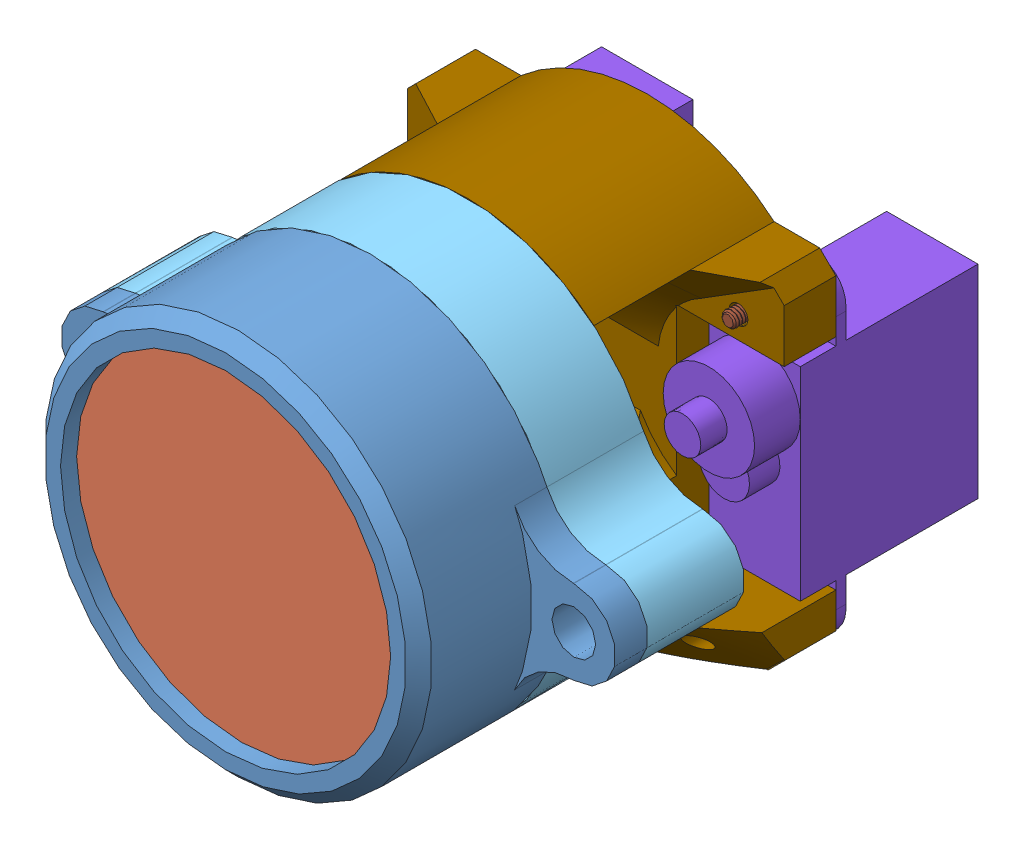
SolidWorks assembly Hydraulic Pressure Indicator, configuration Default. Lengths in mm.
Overall size (127.75 115.27 55.56).
32 component instances, 13 part files, 73 mates.
Components (placement in the parent):
- 1.5 IN Case-1: 1.5 IN Case [Default] x (1 0 0) z (0 -1 0) size (54.61 14.29 38.1)
- 1.5 Indicator Glass-1: 1.5 Indicator Glass [Default] at (0 0 -1.5875) x (-1 0 0) z (0 0 -1) size (32.84 32.84 1.59)
- Battery Voltage Indicator Spacer-1: Battery Voltage Indicator Spacer [Default] at (0 0 -3.175) x (-1 0 0) z (0 0 -1) size (32.84 32.84 6.35)
- Hydraulic Indicator Bezel Face-1: Hydraulic Indicator Bezel Face [Default] at (0 0 -11.1125) x (-1 0 0) z (0 0 1) size (32.84 32.84 1.59)
- 1.5 Indicator Rear Bezel Spacer-1: 1.5 Indicator Rear Bezel Spacer [Default] at (0 0 -11.1125) x (1 0 0) z (0 0 -1) size (54.61 38.1 12.7)
- Hydraulic Pressure Pointer-1: Hydraulic Pressure Pointer [#1 Needle] at (0 0 -8.7312) x (-0.207912 0.978148 0) z (0 0 1) size (8.26 18.1 1.59)
- Hydraulic Pressure Pointer-2: Hydraulic Pressure Pointer [#2 Needle] at (0 0 -6.35) x (-0.207912 0.978148 0) z (0 0 1) size (8.26 18.1 1.59)
- 93365A130_BRASS HEAT-SET INSERT FOR PLASTICS_6-32-3: 93365A130_BRASS HEAT-SET INSERT FOR PLASTICS_6-32 [93365A130] at (23.1775 0 -14.2875) x (1 0 0) z (0 -1 0) size (5.56 4.29 5.56)
- 93365A130_BRASS HEAT-SET INSERT FOR PLASTICS_6-32-4: 93365A130_BRASS HEAT-SET INSERT FOR PLASTICS_6-32 [93365A130] at (-23.1775 0 -14.2875) x (1 0 0) z (0 -1 0) size (5.56 4.29 5.56)
- spur gear_ai-1: spur gear_ai [PreviewCfg] at (0 0 -24.6062) x (0 0 -1) z (0.923728 0.383049 0) size (12.7 86.43 86.43)
- spur gear_ai-2: spur gear_ai [PreviewCfg] at (-14.0335 2.325 -27.7812) x (0 0 1) z (-1 0 0) size (12.7 86.43 86.43)
- spur gear_ai-3: spur gear_ai [PreviewCfg] at (0 0 -29.3687) x (0 0 -1) z (0.923728 0.383049 0) size (12.7 86.43 86.43)
- spur gear_ai-4: spur gear_ai [PreviewCfg] at (14.0335 2.325 -32.5438) x (0 0 1) z (-0.923728 -0.383049 0) size (12.7 86.43 86.43)
- SERVO, SUB-NANO, 3.7G, GENERIC-3: SERVO, SUB-NANO, 3.7G, GENERIC [Default] at (9.5335 -13.175 -55.5562) size (9.5 32.5 24.6)
- SERVO, SUB-NANO, 3.7G, GENERIC-4: SERVO, SUB-NANO, 3.7G, GENERIC [Default] at (-18.5335 -13.175 -55.5562) size (9.5 32.5 24.6)
- HYD PRESS SERVO MOUNT-1: HYD PRESS SERVO MOUNT [Default] at (0 0 -23.8125) x (1 0 0) z (0 0 -1) size (37.07 38.1 17.74)
- 93365A102 - INSERT, 0-80, BRASS, FOR PLASTICS-1: 93365A102 - INSERT, 0-80, BRASS, FOR PLASTICS [Default] at (-14.0335 -16.175 -41.5563) x (-0.425487 0.904965 0) z (-0.904965 -0.425487 0) size (3.58 3.01 3.58)
- 91772A061_18-8 SS PAN HEAD PHILLIPS MACHINE SCREW_#0-80 X .2812-1: 91772A061_18-8 SS PAN HEAD PHILLIPS MACHINE SCREW_#0-80 X .2812 [91772A061] at (-14.0335 -16.175 -35.4125) x (-0.994174 -0.107783 0) z (0 0 -1) size (2.95 2.95 8.26)
- 91772A061_18-8 SS PAN HEAD PHILLIPS MACHINE SCREW_#0-80 X .2812-2: 91772A061_18-8 SS PAN HEAD PHILLIPS MACHINE SCREW_#0-80 X .2812 [91772A061] at (14.0335 9.825 -35.4125) x (-0.994174 -0.107783 0) z (0 0 -1) size (2.95 2.95 8.26)
- 91772A061_18-8 SS PAN HEAD PHILLIPS MACHINE SCREW_#0-80 X .2812-3: 91772A061_18-8 SS PAN HEAD PHILLIPS MACHINE SCREW_#0-80 X .2812 [91772A061] at (-14.0335 9.825 -35.4125) x (-0.994174 -0.107783 0) z (0 0 -1) size (2.95 2.95 8.26)
- 91772A061_18-8 SS PAN HEAD PHILLIPS MACHINE SCREW_#0-80 X .2812-4: 91772A061_18-8 SS PAN HEAD PHILLIPS MACHINE SCREW_#0-80 X .2812 [91772A061] at (14.0335 -16.175 -35.4125) x (-0.994174 -0.107783 0) z (0 0 -1) size (2.95 2.95 8.26)
- 93365A102 - INSERT, 0-80, BRASS, FOR PLASTICS-2: 93365A102 - INSERT, 0-80, BRASS, FOR PLASTICS [Default] at (14.0335 9.825 -41.5563) x (-0.425487 0.904965 0) z (-0.904965 -0.425487 0) size (3.58 3.01 3.58)
- 93365A102 - INSERT, 0-80, BRASS, FOR PLASTICS-3: 93365A102 - INSERT, 0-80, BRASS, FOR PLASTICS [Default] at (-14.0335 9.825 -41.5563) x (-0.425487 0.904965 0) z (-0.904965 -0.425487 0) size (3.58 3.01 3.58)
- 93365A102 - INSERT, 0-80, BRASS, FOR PLASTICS-4: 93365A102 - INSERT, 0-80, BRASS, FOR PLASTICS [Default] at (14.0335 -16.175 -41.5563) x (-0.425487 0.904965 0) z (-0.904965 -0.425487 0) size (3.58 3.01 3.58)
- 91772A064 - PHS, 0-80 x .4375, 18-8-1: 91772A064 - PHS, 0-80 x .4375, 18-8 [91772A064] at (7.435 -14.6946 -28.575) x (-0.345103 0.938565 0) z (0 0 1) size (2.95 2.95 12.24)
- 93365A102 - INSERT, 0-80, BRASS, FOR PLASTICS-5: 93365A102 - INSERT, 0-80, BRASS, FOR PLASTICS [Default] at (7.435 -14.6946 -23.8125) x (-0.142747 -0.989759 0) z (-0.989759 0.142747 0) size (3.58 3.01 3.58)
- 93365A102 - INSERT, 0-80, BRASS, FOR PLASTICS-6: 93365A102 - INSERT, 0-80, BRASS, FOR PLASTICS [Default] at (-7.7474 -14.6946 -23.8125) x (-0.142747 -0.989759 0) z (-0.989759 0.142747 0) size (3.58 3.01 3.58)
- 93365A102 - INSERT, 0-80, BRASS, FOR PLASTICS-7: 93365A102 - INSERT, 0-80, BRASS, FOR PLASTICS [Default] at (-7.7474 14.6946 -23.8125) x (-0.142747 -0.989759 0) z (-0.989759 0.142747 0) size (3.58 3.01 3.58)
- 93365A102 - INSERT, 0-80, BRASS, FOR PLASTICS-8: 93365A102 - INSERT, 0-80, BRASS, FOR PLASTICS [Default] at (7.435 14.6946 -23.8125) x (-0.142747 -0.989759 0) z (-0.989759 0.142747 0) size (3.58 3.01 3.58)
- 91772A064 - PHS, 0-80 x .4375, 18-8-2: 91772A064 - PHS, 0-80 x .4375, 18-8 [91772A064] at (-7.7474 -14.6946 -28.575) x (-0.345103 0.938565 0) z (0 0 1) size (2.95 2.95 12.24)
- 91772A064 - PHS, 0-80 x .4375, 18-8-3: 91772A064 - PHS, 0-80 x .4375, 18-8 [91772A064] at (-7.7474 14.6946 -28.575) x (-0.345103 0.938565 0) z (0 0 1) size (2.95 2.95 12.24)
- 91772A064 - PHS, 0-80 x .4375, 18-8-4: 91772A064 - PHS, 0-80 x .4375, 18-8 [91772A064] at (7.435 14.6946 -28.575) x (-0.345103 0.938565 0) z (0 0 1) size (2.95 2.95 12.24)
Mates (geometry in assembly coordinates):
- Coincident1: coincident aligned: plane of 1.5 IN Case-1 through (0 0 0) normal (1 0 0); plane of assembly through (0 0 0) normal (1 0 0)
- Coincident2: coincident aligned: plane of 1.5 IN Case-1 through (0 0 0) normal (0 0 1); plane of assembly through (0 0 0) normal (0 0 1)
- Coincident3: coincident anti-aligned: plane of 1.5 IN Case-1 through (0 0 0) normal (0 -1 0); plane of assembly through (0 0 0) normal (0 1 0)
- InPlace1: in place: plane of 1.5 IN Case-1 through (0 0 -1.5875) normal (0 0 -1); plane of 1.5 Indicator Glass-1 through (0 0 -1.5875) normal (0 0 -1); moOrthogonalPlaneRef_w of 1.5 IN Case-1 through (0 0 -1.5875) normal (0 0 -1); unknown of 1.5 Indicator Glass-1; plane of 1.5 IN Case-1 through (0 0 -1.5875) normal (0 0 -1); plane of 1.5 Indicator Glass-1 through (0 0 -1.5875) normal (-1 0 0); plane of 1.5 IN Case-1 through (0 0 -1.5875) normal (0 0 -1); unknown of 1.5 Indicator Glass-1
- Coincident4: coincident aligned: plane of ?; plane of ?
- Coincident5: coincident aligned: moOrthogonalPlaneRef_w of 1.5 IN Case-1 through (0 0 -1.5875) normal (0 1 0); plane of 1.5 Indicator Glass-1 through (0 0 -1.5875) normal (0 1 0)
- Coincident6: coincident anti-aligned: moOrthogonalPlaneRef_w of 1.5 IN Case-1 through (0 0 -1.5875) normal (1 0 0); plane of 1.5 Indicator Glass-1 through (0 0 -1.5875) normal (-1 0 0)
- InPlace2: in place: plane of 1.5 Indicator Glass-1 through (0 0 -3.175) normal (0 0 -1); plane of Battery Voltage Indicator Spacer-1 through (0 0 -3.175) normal (0 0 -1); plane of 1.5 Indicator Glass-1 through (0 0 -3.175) normal (0 0 -1); unknown of Battery Voltage Indicator Spacer-1; plane of 1.5 Indicator Glass-1 through (0 0 -3.175) normal (0 0 -1); plane of Battery Voltage Indicator Spacer-1 through (0 0 -3.175) normal (-1 0 0); plane of 1.5 Indicator Glass-1 through (0 0 -3.175) normal (0 0 -1); unknown of Battery Voltage Indicator Spacer-1
- Coincident7: coincident aligned: plane of ?; plane of ?
- Coincident8: coincident aligned: moOrthogonalPlaneRef_w of 1.5 Indicator Glass-1 through (0 0 -3.175) normal (0 1 0); plane of Battery Voltage Indicator Spacer-1 through (0 0 -3.175) normal (0 1 0)
- Coincident9: coincident anti-aligned: moOrthogonalPlaneRef_w of 1.5 Indicator Glass-1 through (0 0 -3.175) normal (1 0 0); plane of Battery Voltage Indicator Spacer-1 through (0 0 -3.175) normal (-1 0 0)
- Concentric1: concentric anti-aligned: cylinder of 1.5 IN Case-1 through (0 0 -1.5875) axis (0 0 1) radius 19.05; cylinder of Hydraulic Indicator Bezel Face-1 through (0 0 -9.525) axis (0 0 -1) radius 16.4211
- Coincident13: coincident anti-aligned: plane of Hydraulic Indicator Bezel Face-1 through (0 0 -11.1125) normal (-1 0 0); plane of assembly through (0 0 0) normal (1 0 0)
- Coincident14: coincident anti-aligned: plane of Battery Voltage Indicator Spacer-1 through (0 0 -9.525) normal (0 0 -1); plane of Hydraulic Indicator Bezel Face-1 through (0 0 -9.525) normal (0 0 1)
- InPlace5: in place: plane of ? through (0 0 -32.6375) normal (0 0 -1); plane of ? through (0 0 -32.6375) normal (0 0 -1); plane of ? through (0 0 -32.6375) normal (0 0 -1); unknown of ?; plane of ? through (0 0 -32.6375) normal (0 0 -1); plane of ? through (0 0 -32.6375) normal (-1 0 0); plane of ? through (0 0 -40.9243) normal (0 0 -1); unknown of ?
- Coincident29: coincident aligned: plane of ?; plane of ?
- Coincident30: coincident aligned: moOrthogonalPlaneRef_w of Needle #2 Concentric Needle Shaft-1; plane of Needle #1 Concetric Needle Shaft-1 through (0 0 -28.4125) normal (0.190115 0.981762 0)
- Coincident31: coincident anti-aligned: moOrthogonalPlaneRef_w of Needle #2 Concentric Needle Shaft-1; plane of Needle #1 Concetric Needle Shaft-1 through (0 0 -28.4125) normal (-0.981762 0.190115 0)
- Concentric30: concentric aligned: cylinder of Needle #2 Concentric Needle Shaft-1 through (0 0 0.9475) axis (0 0 -1) radius 3.175; cylinder of Hydraulic Pressure Pointer-1 through (0 0 -7.1437) axis (0 0 -1) radius 3.302
- Concentric31: concentric: cylinder of Needle #1 Concetric Needle Shaft-1 through (0 0 -45.6026) axis (0 0 1) radius 1.5875; cylinder of Hydraulic Pressure Pointer-2 through (0 0 -4.7625) axis (0 0 -1) radius 1.651
- Coincident78: coincident: plane of ? through (0 0 -4.7625) normal (0 0 1); plane of Hydraulic Pressure Pointer-2 through (0 0 -4.7625) normal (0 0 1)
- Distance11: distance = 0.7937 mm: plane of Hydraulic Pressure Pointer-1 through (0 0 -7.1437) normal (0 0 1); plane of Hydraulic Pressure Pointer-2 through (0 0 -6.35) normal (0 0 -1)
- Width5: width anti-aligned: plane of Hydraulic Pressure Pointer-1 through (-3.3967 -2.345 -7.1437) normal (0.207912 -0.978148 0); plane of Hydraulic Indicator Bezel Face-1 through (-4.0568 0.7607 -7.1437) normal (-0.207912 0.978148 0); plane of Hydraulic Pressure Pointer-1 through (-13.3759 -3.1028 -9.525) normal (-0.207912 0.978148 0); plane of Hydraulic Indicator Bezel Face-1 through (-13.4815 -2.6059 -9.525) normal (0.207912 -0.978148 0)
- Coincident79: coincident aligned: plane of Hydraulic Pressure Pointer-1 through (-3.3967 -2.345 -7.1437) normal (0.207912 -0.978148 0); plane of Hydraulic Pressure Pointer-2 through (-3.3967 -2.345 -4.7625) normal (0.207912 -0.978148 0)
- Concentric63: concentric aligned: cylinder of Hydraulic Indicator Bezel Face-1 through (0 0 -9.525) axis (0 0 -1) radius 3.302; cylinder of VID28-05-1 through (0 0 -47.5625) axis (0 0 -1) radius 0.75
- Parallel5: parallel aligned: plane of VID28-05-1 through (-9.5 0 -47.5625) normal (1 0 0); plane of assembly through (0 0 0) normal (1 0 0)
- Distance12: distance = 25.4 mm aligned: plane of VID28-05-1 through (0 0 -30.1625) normal (0 0 1); plane of Hydraulic Pressure Pointer-2 through (0 0 -4.7625) normal (0 0 1)
- InPlace14: in place: plane of Hydraulic Indicator Bezel Face-1 through (0 0 -11.1125) normal (0 0 -1); plane of ? through (0 0 -11.1125) normal (0 0 -1); plane of Hydraulic Indicator Bezel Face-1 through (0 0 -11.1125) normal (0 0 -1); plane of ? through (0 0 -11.1125) normal (0 1 0); plane of Hydraulic Indicator Bezel Face-1 through (0 0 -11.1125) normal (0 0 -1); plane of ? through (0 0 -11.1125) normal (-1 0 0); plane of Hydraulic Indicator Bezel Face-1 through (0 0 -11.1125) normal (0 0 -1); unknown of 1.5 Indicator Rear Bezel Spacer-1
- Coincident112: coincident aligned: plane of ?; plane of ?
- Coincident113: coincident aligned: moOrthogonalPlaneRef_w of Hydraulic Indicator Bezel Face-1 through (0 0 -11.1125) normal (0 -1 0); plane of 1.5 Indicator Rear Bezel Spacer-1 through (0 0 -11.1125) normal (0 -1 0)
- Coincident114: coincident anti-aligned: moOrthogonalPlaneRef_w of Hydraulic Indicator Bezel Face-1 through (0 0 -11.1125) normal (-1 0 0); plane of 1.5 Indicator Rear Bezel Spacer-1 through (0 0 -11.1125) normal (1 0 0)
- Coincident115: coincident aligned: plane of Hydraulic Pressure Pointer-2 through (0 0 -4.7625) normal (0 0 1); plane of Needle #1 Concetric Needle Shaft-1 through (0 0 -4.7625) normal (0 0 1)
- Concentric64: concentric anti-aligned: cylinder of Hydraulic Pressure Pointer-2 through (0 0 -4.7625) axis (0 0 -1) radius 1.651; cylinder of Needle #1 Concetric Needle Shaft-1 through (0 0 -45.6026) axis (0 0 1) radius 1.5875
- Concentric65: concentric anti-aligned: cylinder of Needle #1 Concetric Needle Shaft-1 through (0 0 -45.6026) axis (0 0 1) radius 1.5875; cylinder of Needle #2 Concentric Needle Shaft-1 through (0 0 0.9475) axis (0 0 -1) radius 3.175
- Coincident117: coincident aligned: plane of Hydraulic Pressure Pointer-1 through (0 0 -7.1437) normal (0 0 1); plane of Needle #2 Concentric Needle Shaft-1 through (0 0 -7.1437) normal (0 0 1)
- Concentric66: concentric anti-aligned: cone of 1.5 Indicator Rear Bezel Spacer-1 through (23.1775 0 -14.2875) axis (0 0 -1); cylinder of 93365A130_BRASS HEAT-SET INSERT FOR PLASTICS_6-32-3 through (23.1775 0 -14.2875) axis (0 0 1) radius 2.5273
- Coincident118: coincident aligned: plane of 1.5 Indicator Rear Bezel Spacer-1 through (23.1775 0 -14.2875) normal (0 0 1); plane of 93365A130_BRASS HEAT-SET INSERT FOR PLASTICS_6-32-3 through (23.1775 0 -14.2875) normal (0 0 1)
- Concentric67: concentric anti-aligned: cone of 1.5 Indicator Rear Bezel Spacer-1 through (-23.1775 0 -14.2875) axis (0 0 -1); cylinder of 93365A130_BRASS HEAT-SET INSERT FOR PLASTICS_6-32-4 through (-23.1775 0 -14.2875) axis (0 0 1) radius 2.5273
- Coincident119: coincident aligned: plane of 1.5 Indicator Rear Bezel Spacer-1 through (23.1775 0 -14.2875) normal (0 0 1); plane of 93365A130_BRASS HEAT-SET INSERT FOR PLASTICS_6-32-4 through (-23.1775 0 -14.2875) normal (0 0 1)
- Concentric68: concentric aligned: cylinder of Hydraulic Pressure Pointer-2 through (0 0 -4.7625) axis (0 0 -1) radius 1.651; cylinder of SHAFT, NEEDLE #1, HYD PRESS GAUGE-1 through (0 0 -4.7625) axis (0 0 -1) radius 1.5875
- Coincident120: coincident aligned: plane of Hydraulic Pressure Pointer-2 through (0 0 -4.7625) normal (0 0 1); plane of SHAFT, NEEDLE #1, HYD PRESS GAUGE-1 through (0 0 -4.7625) normal (0 0 1)
- Concentric72: concentric: cylinder of Hydraulic Indicator Bezel Face-1 through (0 0 -9.525) axis (0 0 -1) radius 3.302; cylinder of SHAFT, NEEDLE #1, DUAL POINTER-1 through (0 0 -7.1437) axis (0 0 -1) radius 3.175
- Coincident125: coincident aligned: plane of Hydraulic Pressure Pointer-1 through (0 0 -7.1437) normal (0 0 1); plane of SHAFT, NEEDLE #1, DUAL POINTER-1 through (0 0 -7.1437) normal (0 0 1)
- Concentric73: concentric aligned: cylinder of Hydraulic Pressure Pointer-2 through (0 0 -4.7625) axis (0 0 -1) radius 1.651; cylinder of SHAFT, NEEDLE #2, DUAL POINTER-1 through (0 0 -4.7625) axis (0 0 -1) radius 1.5875
- Coincident126: coincident aligned: plane of Hydraulic Pressure Pointer-2 through (0 0 -4.7625) normal (0 0 1); plane of SHAFT, NEEDLE #2, DUAL POINTER-1 through (0 0 -4.7625) normal (0 0 1)
- Parallel7: parallel anti-aligned: plane of 1.5 Indicator Rear Bezel Spacer-1 through (23.1775 0 -23.8125) normal (0 0 -1); plane of HYD PRESS GAUGE DRIVE GEAR-2 through (-14.0335 2.325 -15.0812) normal (0 0 1)
- Tangent3: tangent: circle of SHAFT, NEEDLE #1, DUAL POINTER-1; circle of HYD PRESS GAUGE DRIVE GEAR-2
- Parallel8: parallel aligned: plane of HYD PRESS GAUGE DRIVE GEAR-2 through (-14.0335 2.325 -27.7812) normal (0 0 -1); plane of HYD PRESS GAUGE DRIVE GEAR-1 through (14.0335 2.325 -32.5438) normal (0 0 -1)
- Tangent4: tangent: circle of SHAFT, NEEDLE #2, DUAL POINTER-1; circle of HYD PRESS GAUGE DRIVE GEAR-1
- Parallel9: parallel anti-aligned: plane of SERVO, SUB-NANO, 3.7G, GENERIC-3 through (9.5335 9.335 -55.5662) normal (-1 0 0)
- Concentric74: concentric: cylinder of HYD PRESS GAUGE DRIVE GEAR-1 through (14.0335 2.325 -21.511) axis (0 0 -1) radius 2.7781; cylinder of SERVO, SUB-NANO, 3.7G, GENERIC-3 through (14.0335 2.325 -33.5563) axis (0 0 -1) radius 4.5
- Coincident127: coincident: plane of HYD PRESS GAUGE DRIVE GEAR-1 through (14.0335 2.325 -30.9563) normal (0 0 -1); plane of SERVO, SUB-NANO, 3.7G, GENERIC-3 through (12.2235 0.515 -30.9563) normal (0 0 1)
- Symmetric3: symmetric aligned: plane of SERVO, SUB-NANO, 3.7G, GENERIC-3 through (8.6085 -10 -55.5662) normal (0 -1 0); plane of SERVO, SUB-NANO, 3.7G, GENERIC-3 through (17.6285 10 -55.5662) normal (0 1 0)
- Concentric75: concentric: cylinder of HYD PRESS GAUGE DRIVE GEAR-2 through (-14.0335 2.325 -30.9563) axis (0 0 1) radius 3.175; cylinder of SERVO, SUB-NANO, 3.7G, GENERIC-4 through (-14.0335 2.325 -30.9563) axis (0 0 -1) radius 1.8
- Coincident128: coincident: plane of HYD PRESS GAUGE DRIVE GEAR-2 through (-14.0335 2.325 -30.9563) normal (0 0 -1); plane of SERVO, SUB-NANO, 3.7G, GENERIC-4 through (-15.8435 0.515 -30.9563) normal (0 0 1)
- Coincident129: coincident aligned: plane of SERVO, SUB-NANO, 3.7G, GENERIC-3 through (9.5235 -13.175 -55.5662) normal (0 -1 0); plane of SERVO, SUB-NANO, 3.7G, GENERIC-4 through (-18.5435 -13.175 -55.5662) normal (0 -1 0)
- Distance14: distance = 3.175 mm: plane of assembly through (0 0 0) normal (0 1 0); plane of SERVO, SUB-NANO, 3.7G, GENERIC-3 through (9.5335 -3.175 -55.5562) normal (0 1 0); plane of assembly
- InPlace15: in place: plane of 1.5 Indicator Rear Bezel Spacer-1 through (23.1775 0 -23.8125) normal (0 0 -1); plane of ? through (0 0 -23.8125) normal (0 0 -1); plane of 1.5 Indicator Rear Bezel Spacer-1 through (23.1775 0 -23.8125) normal (0 0 -1); plane of ? through (0 0 -23.8125) normal (0 1 0); plane of 1.5 Indicator Rear Bezel Spacer-1 through (23.1775 0 -23.8125) normal (0 0 -1); plane of ? through (0 0 -23.8125) normal (-1 0 0); plane of 1.5 Indicator Rear Bezel Spacer-1 through (23.1775 0 -23.8125) normal (0 0 -1); unknown of HYD PRESS SERVO MOUNT-1
- Coincident130: coincident aligned: plane of ?; plane of ?
- Coincident131: coincident aligned: moOrthogonalPlaneRef_w of 1.5 Indicator Rear Bezel Spacer-1 through (0 0 -23.8125) normal (0 -1 0); plane of Part5^Hydraulic Pressure Indicator-1 through (0 0 -23.8125) normal (0 -1 0)
- Coincident132: coincident anti-aligned: moOrthogonalPlaneRef_w of 1.5 Indicator Rear Bezel Spacer-1 through (0 0 -23.8125) normal (-1 0 0); plane of Part5^Hydraulic Pressure Indicator-1 through (0 0 -23.8125) normal (1 0 0)
- InPlace16: in place: plane of 1.5 Indicator Rear Bezel Spacer-1 through (23.1775 0 -23.8125) normal (0 0 -1); plane of ? through (0 0 -23.8125) normal (0 0 -1); plane of 1.5 Indicator Rear Bezel Spacer-1 through (23.1775 0 -23.8125) normal (0 0 -1); plane of ? through (0 0 -23.8125) normal (0 1 0); plane of 1.5 Indicator Rear Bezel Spacer-1 through (23.1775 0 -23.8125) normal (0 0 -1); plane of ? through (0 0 -23.8125) normal (-1 0 0); plane of 1.5 Indicator Rear Bezel Spacer-1 through (23.1775 0 -23.8125) normal (0 0 -1); unknown of HYD PRESS SERVO MOUNT-1
- Coincident133: coincident aligned: plane of ?; plane of ?
- Coincident134: coincident aligned: moOrthogonalPlaneRef_w of 1.5 Indicator Rear Bezel Spacer-1 through (0 0 -23.8125) normal (0 -1 0); plane of Part6^Hydraulic Pressure Indicator-1 through (0 0 -23.8125) normal (0 -1 0)
- Coincident135: coincident anti-aligned: moOrthogonalPlaneRef_w of 1.5 Indicator Rear Bezel Spacer-1 through (0 0 -23.8125) normal (-1 0 0); plane of Part6^Hydraulic Pressure Indicator-1 through (0 0 -23.8125) normal (1 0 0)
- Concentric76: concentric anti-aligned: cylinder of 91772A061_18-8 SS PAN HEAD PHILLIPS MACHINE SCREW_#0-80 X .2812-1 through (-14.0335 -16.175 -35.4125) axis (0 0 1) radius 1.4732; circle of 93365A102 - INSERT, 0-80, BRASS, FOR PLASTICS-1
- Concentric77: concentric aligned: cone of HYD PRESS SERVO MOUNT-1 through (-14.0335 -16.175 -41.5563) axis (0 0 1); cone of 93365A102 - INSERT, 0-80, BRASS, FOR PLASTICS-1 through (-14.0335 -16.175 -40.4463) axis (0 0 1)
- Coincident136: coincident aligned: plane of HYD PRESS SERVO MOUNT-1 through (18.5436 -13.165 -41.5563) normal (0 0 -1); plane of 93365A102 - INSERT, 0-80, BRASS, FOR PLASTICS-1 through (-13.2716 -17.7955 -41.5563) normal (0 0 -1)
- Coincident137: coincident anti-aligned: plane of SERVO, SUB-NANO, 3.7G, GENERIC-4 through (-18.5436 -13.165 -42.5562) normal (0 0 -1); plane of 91772A061_18-8 SS PAN HEAD PHILLIPS MACHINE SCREW_#0-80 X .2812-1 through (-14.0335 -16.175 -42.5562) normal (0 0 1)
- Concentric78: concentric anti-aligned: cylinder of 91772A064 - PHS, 0-80 x .4375, 18-8-1 through (7.435 -14.6946 -28.575) axis (0 0 -1) radius 1.4732; circle of 93365A102 - INSERT, 0-80, BRASS, FOR PLASTICS-5
- Concentric79: concentric anti-aligned: cylinder of HYD PRESS SERVO MOUNT-1 through (7.435 -14.6946 -23.8125) axis (0 0 1) radius 0.9271; cone of 93365A102 - INSERT, 0-80, BRASS, FOR PLASTICS-5 through (7.435 -14.6946 -24.9225) axis (0 0 -1)
- Coincident138: coincident aligned: plane of HYD PRESS SERVO MOUNT-1 through (-14.0335 2.325 -23.8125) normal (0 0 1); plane of 93365A102 - INSERT, 0-80, BRASS, FOR PLASTICS-5 through (7.6907 -12.9222 -23.8125) normal (0 0 1)
- Coincident139: coincident anti-aligned: plane of 1.5 Indicator Rear Bezel Spacer-1 through (8.3621 -14.6946 -17.4625) normal (0 0 1); plane of 91772A064 - PHS, 0-80 x .4375, 18-8-1 through (7.435 -14.6946 -17.4625) normal (0 0 -1)
